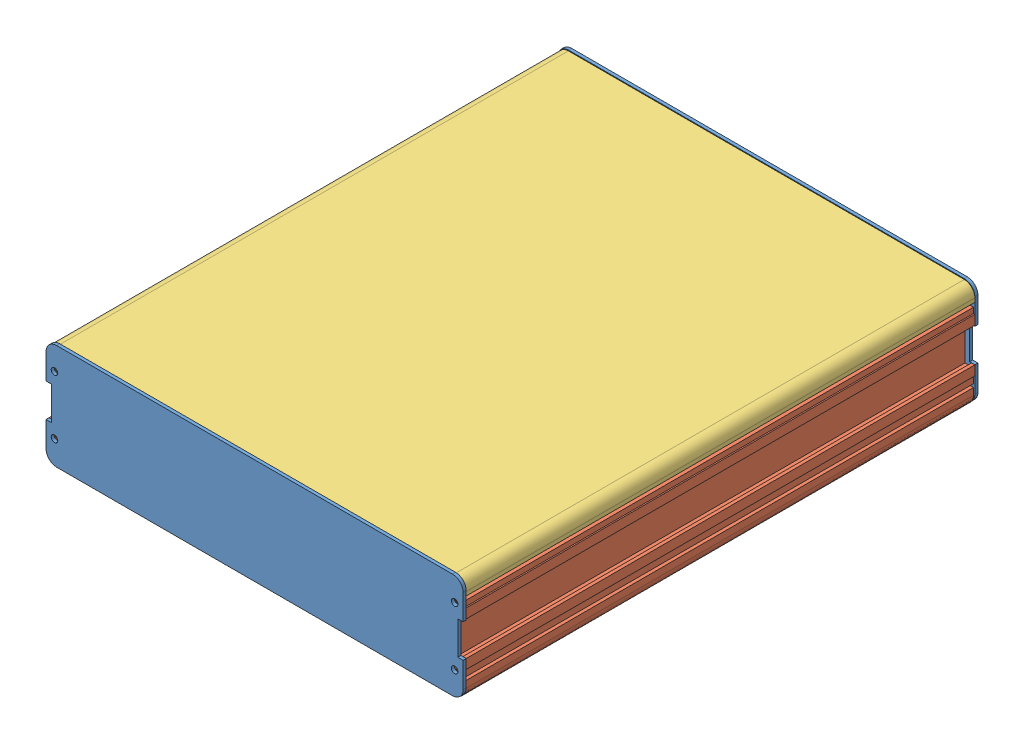
SolidWorks assembly MW_PRiME_IA6161, configuration Simplified. Lengths in mm.
Overall size (249.94 64.12 308.51).
4 component instances, 4 part files, 11 mates.
Components (placement in the parent):
- PRiME_IA-6161_Panel-1: PRiME_IA-6161_Panel [Default] at (124.968 32.5438 23.622) x (-1 0 0) z (0 0 -1) size (249.94 63.14 1.85)
- PRiME_IA-6161_BackPanel-1: PRiME_IA-6161_BackPanel [Default] at (124.968 32.5438 328.422) x (-1 0 0) z (0 0 1) size (249.94 63.14 1.85)
- PRiME_IA-6161_MainBody-2: PRiME_IA-6161_MainBody [Default] at (124.968 52.07 328.422) x (-1 0 0) z (0 0 -1) size (249.94 52.07 304.8)
- PRiME_IA-6161_Lid-1: PRiME_IA-6161_Lid [Default] at (124.968 63.6595 328.422) x (-1 0 0) z (0 0 -1) size (249.94 15.75 304.8)
Mates (geometry in assembly coordinates):
- Coincident15: coincident anti-aligned: plane of PRiME_IA-6161_MainBody-2 through (124.968 52.07 0) normal (0 0 -1); plane of assembly through (0 0 0) normal (0 0 1)
- Coincident16: coincident aligned: plane of PRiME_IA-6161_MainBody-2; plane of assembly through (0 0 0) normal (0 1 0)
- Coincident17: coincident anti-aligned: plane of PRiME_IA-6161_MainBody-2 through (0 52.07 328.422) normal (-1 0 0); plane of assembly through (0 0 0) normal (1 0 0)
- Coincident24: coincident anti-aligned: plane of PRiME_IA-6161_Panel-1 through (124.968 32.5438 23.622) normal (0 0 1); plane of PRiME_IA-6161_MainBody-2 through (124.968 52.07 23.622) normal (0 0 -1)
- Coincident27: coincident anti-aligned: line of PRiME_IA-6161_Panel-1 through (5.08 15.0812 23.622) axis (0 0 -1); line of PRiME_IA-6161_MainBody-2 through (5.08 15.0812 23.622) axis (0 0 1)
- Coincident28: coincident anti-aligned: plane of PRiME_IA-6161_BackPanel-1 through (124.968 32.5438 328.422) normal (0 0 -1); plane of PRiME_IA-6161_MainBody-2 through (124.968 52.07 328.422) normal (0 0 1)
- Coincident29: coincident aligned: line of PRiME_IA-6161_BackPanel-1 through (5.08 50.0063 328.422) axis (0 0 1); line of PRiME_IA-6161_MainBody-2 through (5.08 50.0063 0) axis (0 0 1)
- Coincident31: coincident aligned: line of PRiME_IA-6161_BackPanel-1 through (244.856 50.0063 328.422) axis (0 0 1); line of PRiME_IA-6161_MainBody-2 through (244.856 50.0063 0) axis (0 0 1)
- Coincident32: coincident aligned: line of PRiME_IA-6161_MainBody-2 through (5.08 50.0063 23.622) axis (0 0 1); line of PRiME_IA-6161_Lid-1 through (5.08 50.0063 23.622) axis (0 0 1)
- Coincident34: coincident aligned: line of PRiME_IA-6161_MainBody-2 through (244.856 50.0063 23.622) axis (0 0 1); line of PRiME_IA-6161_Lid-1 through (244.856 50.0063 23.622) axis (0 0 1)
- Coincident35: coincident aligned: plane of PRiME_IA-6161_MainBody-2 through (124.968 52.07 176.022) normal (0 0 -1); plane of PRiME_IA-6161_Lid-1 through (124.968 63.6595 176.022) normal (0 0 -1)
